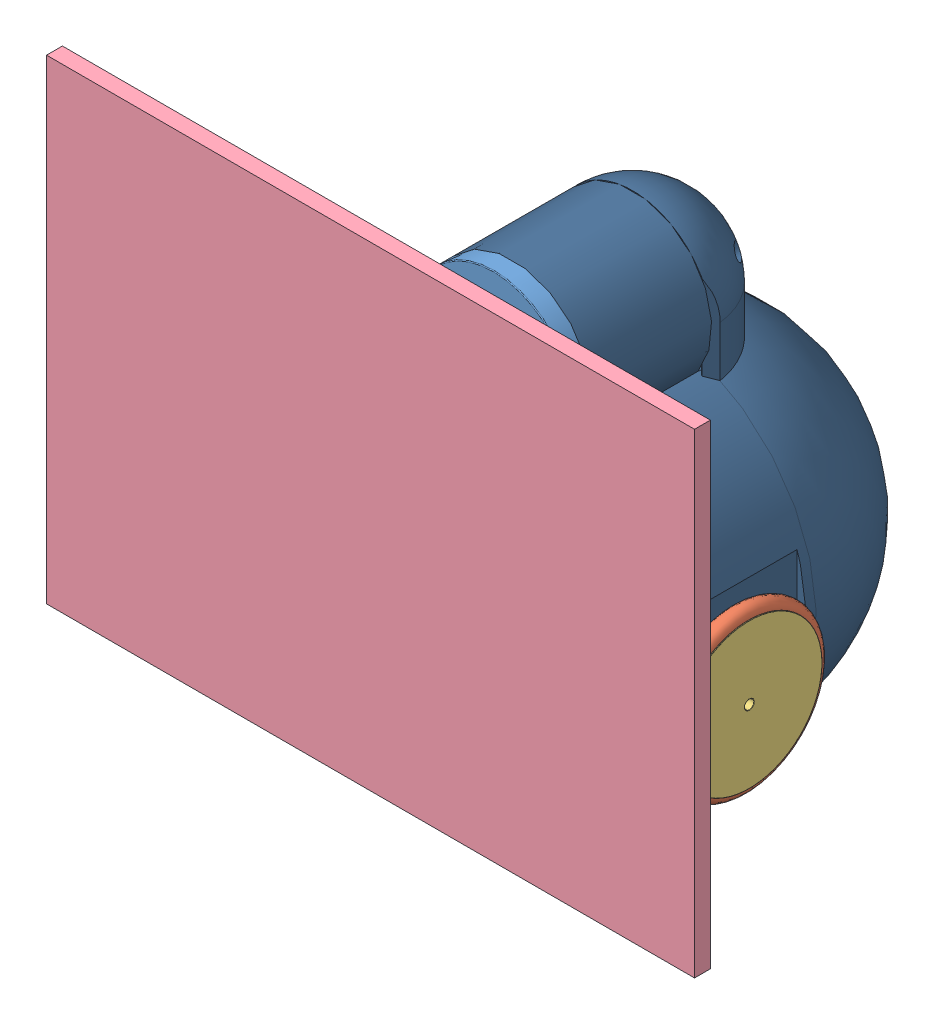
SolidWorks assembly Assemblage avec tous les composants, configuration Défaut. Lengths in mm.
Overall size (204.53 263.78 123.59).
33 component instances, 10 part files, 19 mates.
Components (placement in the parent):
- Robot Tortue-1: Robot Tortue [Défaut] at (122.1999 52.7517 -19.64) x (1 0 0) z (0 0.001694 0.999999) size (110 145 61.03)
- Assemblage Roue-2: Assemblage Roue [Défaut] at (55.5298 2.7943 -33.9422) x (0 -0.930111 0.367278) z (-1 0 0) size (51.28 51.28 16)
  - Joint torique 40,64x5,32-1: Joint torique 40,64x5,32 [Défaut] at (-43.4073 26.0665 1.9899) size (51.28 51.28 5.32)
  - Roue-1: Roue [Défaut] at (-43.4073 26.0665 -0.6701) size (45.96 45.96 16)
- sol-1: sol [Défaut] at origin size (204.53 261.38 5)
- n20 motor-1: n20 motor [轴长10mm] at (85.6113 52.6511 -25.5916) x (1 0 0) z (0 0.001694 0.999999) size (36.2 12.14 10.87)
  - motor-1: motor [默认] at (-3.4114 0.0905 -5.0483) size (19.5 12 10)
  - n20_shaft-1: n20_shaft [10mm] at (-13.1114 0.0905 -0.0483) x (0 -0.354131 -0.935196) z (0 0.935196 -0.354131) size (3 12 3)
  - n20_gearbox-1: n20_gearbox [默认] at (-11.4114 0.0905 -0.0483) x (0 1 0) z (-1 0 0) size (12 10 9.7)
  - cross recessed countersunk head screws gb1-1: cross recessed countersunk head screws gb1 [GB_CROSS_SCREWS_TYPE4 M1.6X3-2  H type-N] at (-12.4614 -3.4095 2.4517) size (3 2.7 2.7)
  - cross recessed countersunk head screws gb1-2: cross recessed countersunk head screws gb1 [GB_CROSS_SCREWS_TYPE4 M1.6X3-2  H type-N] at (-12.4614 3.5905 -2.5483) x (1 0 0) z (0 0.116872 0.993147) size (3 2.7 2.7)
  - spur gear_gb-1: spur gear_gb [GB - Spur gear 0.25M 10T 20PA 2FW ---S10A75H50L1.0N] at (-8.4114 -2.9095 -2.5483) x (1 0 0) z (0 -0.845955 0.533254) size (2 2.87 3)
  - spur gear_gb-2: spur gear_gb [GB - Spur gear 0.25M 10T 20PA 2FW ---S10A75H50L1.0N] at (-4.4114 0.0905 -0.0483) x (-1 0 0) z (0 0.404067 -0.914729) size (2 2.87 3)
  - spur gear_gb-4: spur gear_gb [GB - Spur gear 0.25M 16T 20PA 2FW ---S16A75H50L1.0N] at (-6.4114 -2.9095 -2.5483) x (1 0 0) z (0 -0.712706 0.701463) size (2 4.44 4.44)
  - spur gear_gb-6: spur gear_gb [GB - Spur gear 0.25M 19T 20PA 2FW ---S19A75H50L1.0N] at (-9.9114 0.0905 -0.0483) x (1 0 0) z (0 0.321468 -0.94692) size (2 5.22 5.24)
  - spur gear_gb-8: spur gear_gb [GB - Spur gear 0.25M 11T 20PA 3FW ---S11A75H50L1.0N] at (-10.9114 3.0905 2.9517) x (1 0 0) z (0 -0.604063 0.796937) size (3 3.2 3.23)
  - spur gear_gb-10: spur gear_gb [GB - Spur gear 0.25M 19T 20PA 1FW ---S19A75H50L1.0N] at (-11.4114 0.0905 -0.0483) x (1 0 0) z (0 -0.330889 0.94367) size (1 5.22 5.24)
- n20 motor-2: n20 motor [轴长10mm] at (158.7885 52.8321 -25.5919) x (-1 0 0) z (0 0.001694 0.999999) size (36.2 12.14 10.87)
  - motor-1: motor [默认] at (-3.4114 0.0905 -5.0483) size (19.5 12 10)
  - n20_shaft-1: n20_shaft [10mm] at (-13.1114 0.0905 -0.0483) x (0 -0.354131 -0.935196) z (0 0.935196 -0.354131) size (3 12 3)
  - n20_gearbox-1: n20_gearbox [默认] at (-11.4114 0.0905 -0.0483) x (0 1 0) z (-1 0 0) size (12 10 9.7)
  - cross recessed countersunk head screws gb1-1: cross recessed countersunk head screws gb1 [GB_CROSS_SCREWS_TYPE4 M1.6X3-2  H type-N] at (-12.4614 -3.4095 2.4517) size (3 2.7 2.7)
  - cross recessed countersunk head screws gb1-2: cross recessed countersunk head screws gb1 [GB_CROSS_SCREWS_TYPE4 M1.6X3-2  H type-N] at (-12.4614 3.5905 -2.5483) x (1 0 0) z (0 0.116872 0.993147) size (3 2.7 2.7)
  - spur gear_gb-1: spur gear_gb [GB - Spur gear 0.25M 10T 20PA 2FW ---S10A75H50L1.0N] at (-8.4114 -2.9095 -2.5483) x (1 0 0) z (0 -0.845955 0.533254) size (2 2.87 3)
  - spur gear_gb-2: spur gear_gb [GB - Spur gear 0.25M 10T 20PA 2FW ---S10A75H50L1.0N] at (-4.4114 0.0905 -0.0483) x (-1 0 0) z (0 0.404067 -0.914729) size (2 2.87 3)
  - spur gear_gb-4: spur gear_gb [GB - Spur gear 0.25M 16T 20PA 2FW ---S16A75H50L1.0N] at (-6.4114 -2.9095 -2.5483) x (1 0 0) z (0 -0.712706 0.701463) size (2 4.44 4.44)
  - spur gear_gb-6: spur gear_gb [GB - Spur gear 0.25M 19T 20PA 2FW ---S19A75H50L1.0N] at (-9.9114 0.0905 -0.0483) x (1 0 0) z (0 0.321468 -0.94692) size (2 5.22 5.24)
  - spur gear_gb-8: spur gear_gb [GB - Spur gear 0.25M 11T 20PA 3FW ---S11A75H50L1.0N] at (-10.9114 3.0905 2.9517) x (1 0 0) z (0 -0.604063 0.796937) size (3 3.2 3.23)
  - spur gear_gb-10: spur gear_gb [GB - Spur gear 0.25M 19T 20PA 1FW ---S19A75H50L1.0N] at (-11.4114 0.0905 -0.0483) x (1 0 0) z (0 -0.330889 0.94367) size (1 5.22 5.24)
- Assemblage Roue-3: Assemblage Roue [Défaut] at (188.87 2.5979 -32.6595) x (0 -0.777649 -0.628699) z (1 0 0) size (51.28 51.28 16)
  - Joint torique 40,64x5,32-1: Joint torique 40,64x5,32 [Défaut] at (-43.4073 26.0665 1.9899) size (51.28 51.28 5.32)
  - Roue-1: Roue [Défaut] at (-43.4073 26.0665 -0.6701) size (45.96 45.96 16)
- Pièce1^Assemblage avec tous les composants-1: Pièce1^Assemblage avec tous les composants [Défaut] at (122.1999 52.7517 -19.64) x (-1 0 0) z (0 -0.001694 -0.999999) size (125.93 145 93.37) (virtual)
Mates (geometry in assembly coordinates):
- Tangent2: tangent: curve of Assemblage Roue-2/Joint torique 40,64x5,32-1; plane of sol-1 through (0 0 0) normal (0 0 -1)
- Distance7: distance = 1 mm: plane of n20 motor-1/motor-1 through (82.1999 52.75 -20.64) normal (0 0.001694 0.999999); plane of Robot Tortue-1 through (122.1999 52.7517 -19.64) normal (0 -0.001694 -0.999999)
- Coïncidente35: coincident: plane of Robot Tortue-1 through (73.1999 57.7353 -29.2885) normal (1 0 0); plane of n20 motor-1/n20_gearbox-1 through (73.1999 52.7415 -25.64) normal (-1 0 0)
- Coïncidente36: coincident: line of Robot Tortue-1 through (73.1999 46.7354 -29.2698) axis (0 0.001694 0.999999); line of n20 motor-1/n20_gearbox-1 through (73.1999 46.7347 -29.6298) axis (0 0.001694 0.999999)
- Coaxiale1: concentric: cylinder of Assemblage Roue-2/Roue-1 through (71.1999 52.7415 -25.64) axis (-1 0 0) radius 1.5; cylinder of n20 motor-1/n20_shaft-1 through (62.4999 52.7415 -25.64) axis (1 0 0) radius 1.5
- Distance8: distance = 1 mm: plane of Assemblage Roue-2/Roue-1 through (69.1999 52.7415 -25.64) normal (1 0 0); plane of Robot Tortue-1 through (70.1999 57.7353 -29.2885) normal (-1 0 0)
- Distance9: distance = 1 mm: plane of n20 motor-2/motor-1 through (162.1999 52.75 -20.64) normal (0 0.001694 0.999999); plane of Robot Tortue-1 through (122.1999 52.7517 -19.64) normal (0 -0.001694 -0.999999)
- Coïncidente39: coincident: plane of Robot Tortue-1 through (171.1999 47.7354 -29.2715) normal (-1 0 0); plane of n20 motor-2/n20_gearbox-1 through (171.1999 52.7415 -25.64) normal (1 0 0)
- Coïncidente40: coincident: line of Robot Tortue-1 through (171.1999 58.7353 -29.2902) axis (0 0.001694 0.999999); line of n20 motor-2/n20_gearbox-1 through (171.1999 58.7347 -29.6502) axis (0 0.001694 0.999999)
- Coaxiale2: concentric: cylinder of n20 motor-2/n20_shaft-1 through (181.8999 52.7415 -25.64) axis (-1 0 0) radius 1.5; cylinder of Assemblage Roue-3/Roue-1 through (173.1999 52.7415 -25.64) axis (1 0 0) radius 1.5
- Distance10: distance = 1 mm: plane of Assemblage Roue-3/Roue-1 through (175.1999 52.7415 -25.64) normal (-1 0 0); plane of Robot Tortue-1 through (174.1999 47.7354 -29.2715) normal (1 0 0)
- Coïncidente43: coincident: plane of sol-1 through (0 0 0) normal (0 0 1); plane of assembly through (0 0 0) normal (0 0 1)
- Coïncidente44: coincident: plane of sol-1 through (0 0 0) normal (0 1 0); plane of assembly through (0 0 0) normal (0 1 0)
- Coïncidente45: coincident: plane of sol-1 through (0 0 0) normal (1 0 0); plane of assembly through (0 0 0) normal (1 0 0)
- Tangent4: tangent: face of Assemblage Roue-2/Joint torique 40,64x5,32-1; plane of sol-1 through (0 0 0) normal (0 0 -1)
- Sur place1: in place: plane of ? through (121.6751 46.4083 -19.64) normal (0 -0.000764 -1); plane of ? through (0 -0.015 -19.6045) normal (0 -0.000764 -1); moOrthogonalPlaneRef_w of ? through (121.6751 46.4083 -19.64) normal (0 -0.000764 -1); plane of ? through (0 -0.015 -19.6045) normal (0 1 -0.000764); plane of ? through (121.6751 46.4083 -19.64) normal (0 -0.000764 -1); plane of ? through (0 -0.015 -19.6045) normal (-1 0 0); plane of Robot Tortue-1 through (122.1999 52.7517 -19.64) normal (0 -0.001694 -0.999999); unknown of Pièce1^Assemblage avec tous les composants-1
- Coïncidente46: coincident: plane of Robot Tortue-1; plane of Pièce1^Assemblage avec tous les composants-1
- Coïncidente47: coincident: moOrthogonalPlaneRef_w of Robot Tortue-1; plane of Pièce1^Assemblage avec tous les composants-1 through (122.1999 52.7517 -19.64) normal (0 0.999999 -0.001694)
- Coïncidente48: coincident: moOrthogonalPlaneRef_w of Robot Tortue-1 through (122.1999 52.7517 -19.64) normal (1 0 0); plane of Pièce1^Assemblage avec tous les composants-1 through (122.1999 52.7517 -19.64) normal (-1 0 0)
